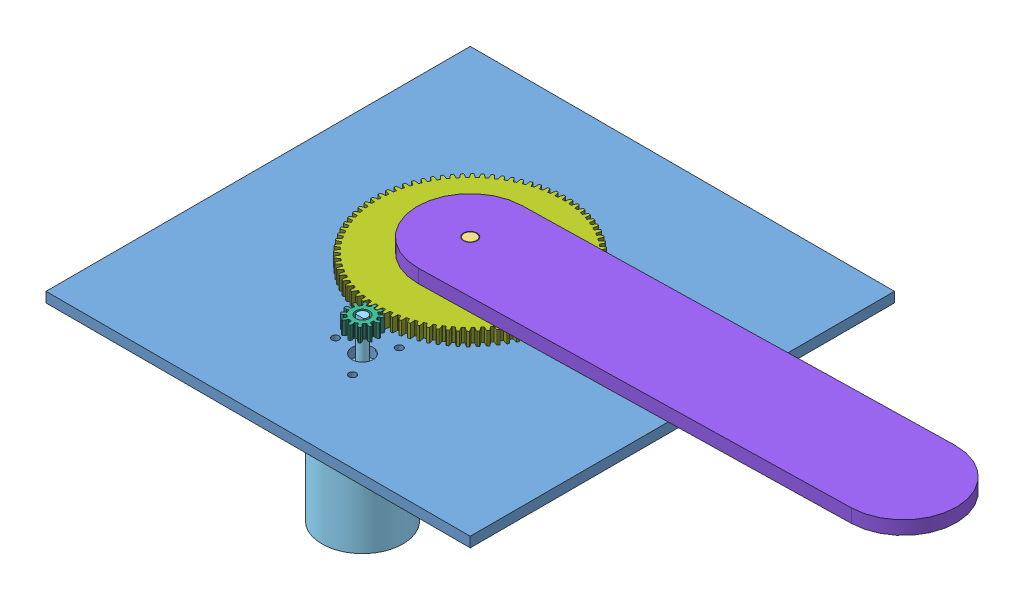
SolidWorks assembly turntable, configuration Default. Lengths in mm.
Overall size (325.48 90.47 200).
14 component instances, 11 part files, 24 mates.
Components (placement in the parent):
- base plate-1: base plate [Default] at (2.5629 -8.9842 3.1335) size (200 4.76 200)
- generic_flanged_ball_bearing-1: generic_flanged_ball_bearing [0.250 x 0.625] at (2.5629 -8.1333 3.1335) x (0 1 0) z (-0.546944 0 0.837169) size (4.98 17.53 17.53)
- generic_dowel_pin-1: generic_dowel_pin [0.25 x 2] at (2.5629 -7.4094 3.1335) x (0 1 0) z (-0.184773 0 -0.982781) size (50.8 6.35 6.35)
- generic_shaft_clamp-1: generic_shaft_clamp [0.25] at (2.5629 1.3219 3.1335) x (0.929398 0 -0.36908) z (0 -1 0) size (17.46 17.45 7.94)
- generic_small_motor-1: generic_small_motor [Default] at (2.5629 -8.9842 53.9335) x (-1 0 0) z (0 1 0) size (38.1 38.1 88.9)
- spur_gear_12_tooth_24_pitch-1: spur_gear_12_tooth_24_pitch [Default] at (2.5629 5.2906 53.9335) x (-0.128453 0 -0.991716) z (0.991716 0 -0.128453) size (14.82 6.35 14.82)
- spur_gear_84_tooth_24_pitch-1: spur_gear_84_tooth_24_pitch [Default] at (2.5629 5.2906 3.1335) x (0.999778 0 -0.021061) z (0.021061 0 0.999778) size (91.02 6.35 91.02)
- rotor-1: rotor [Default] at (2.5629 11.6406 3.1335) x (0.999778 0 -0.021061) z (0.021061 0 0.999778) size (250 6.35 50)
- lower bearing plate-1: lower bearing plate [Default] at (2.5629 -34.3842 3.1335) size (50 6.35 50)
- generic ball bearing-2: generic ball bearing [0.250 x 0.75] at (2.5629 -27.2404 3.1335) x (0 -1 0) z (-0.049783 0 0.99876) size (7.14 19.05 19.05)
- round_threaded_spacer-1: round_threaded_spacer [4-40 x 0.750] at (-18.4371 -8.9842 -17.8665) x (0.531357 0 0.847148) z (0 1 0) size (6.35 6.35 19.05)
- round_threaded_spacer-2: round_threaded_spacer [4-40 x 0.750] at (-18.4371 -8.9842 24.1335) x (0.531357 0 0.847148) z (0 1 0) size (6.35 6.35 19.05)
- round_threaded_spacer-3: round_threaded_spacer [4-40 x 0.750] at (23.5629 -8.9842 -17.8665) x (0.531357 0 0.847148) z (0 1 0) size (6.35 6.35 19.05)
- round_threaded_spacer-4: round_threaded_spacer [4-40 x 0.750] at (23.5629 -8.9842 24.1335) x (0.531357 0 0.847148) z (0 1 0) size (6.35 6.35 19.05)
Mates (geometry in assembly coordinates):
- Concentric1: concentric aligned: cylinder of base plate-1 through (2.5629 -4.2217 3.1335) axis (0 -1 0) radius 7.9375; cylinder of generic_flanged_ball_bearing-1 through (2.5629 -12.9653 3.1335) axis (0 -1 0) radius 7.9375
- Concentric2: concentric aligned: cylinder of generic_flanged_ball_bearing-1 through (2.5629 -12.9653 3.1335) axis (0 -1 0) radius 3.175; cylinder of generic_dowel_pin-1 through (2.5629 17.9906 3.1335) axis (0 -1 0) radius 3.175
- Concentric3: concentric anti-aligned: cylinder of generic_dowel_pin-1 through (2.5629 17.9906 3.1335) axis (0 -1 0) radius 3.175; cylinder of generic_shaft_clamp-1 through (2.5629 -2.6469 3.1335) axis (0 1 0) radius 3.175
- Coincident2: coincident anti-aligned: plane of base plate-1 through (2.5629 -8.9842 3.1335) normal (0 -1 0); plane of generic_small_motor-1 through (2.5629 -8.9842 53.9335) normal (0 1 0)
- Concentric4: concentric aligned: cylinder of generic_dowel_pin-1 through (2.5629 17.9906 3.1335) axis (0 -1 0) radius 3.175; cylinder of spur_gear_84_tooth_24_pitch-1 through (2.5629 11.6406 3.1335) axis (0 -1 0) radius 3.175
- Coincident3: coincident anti-aligned: plane of generic_shaft_clamp-1 through (2.5629 5.2906 3.1335) normal (0 1 0); plane of spur_gear_84_tooth_24_pitch-1 through (2.5629 5.2906 3.1335) normal (0 -1 0)
- Concentric5: concentric aligned: cylinder of generic_small_motor-1 through (2.5629 16.4158 53.9335) axis (0 -1 0) radius 2.3813; cylinder of spur_gear_12_tooth_24_pitch-1 through (2.5629 11.6406 53.9335) axis (0 -1 0) radius 3.175
- Coincident4: coincident aligned: plane of spur_gear_12_tooth_24_pitch-1 through (2.5629 11.6406 53.9335) normal (0 1 0); plane of spur_gear_84_tooth_24_pitch-1 through (2.5629 11.6406 3.1335) normal (0 1 0)
- Distance1: distance = 50.8 mm: axis of generic_dowel_pin-1 through (2.5629 17.7366 3.1335) axis (0 -1 0); axis of generic_small_motor-1 through (2.5629 -72.4842 53.9335) axis (0 1 0)
- Concentric7: concentric anti-aligned: cylinder of generic_dowel_pin-1 through (2.5629 17.9906 3.1335) axis (0 -1 0) radius 3.175; cylinder of rotor-1 through (2.5629 11.6406 3.1335) axis (0 1 0) radius 3.175
- Coincident10: coincident anti-aligned: plane of spur_gear_84_tooth_24_pitch-1 through (2.5629 11.6406 3.1335) normal (0 1 0); plane of rotor-1 through (2.5629 11.6406 3.1335) normal (0 -1 0)
- Coincident6: coincident aligned: plane of generic_dowel_pin-1 through (2.5629 17.9906 3.1335) normal (0 1 0); plane of rotor-1 through (2.5629 17.9906 3.1335) normal (0 1 0)
- Concentric8: concentric aligned: cylinder of generic_dowel_pin-1 through (2.5629 17.9906 3.1335) axis (0 -1 0) radius 3.175; cylinder of lower bearing plate-1 through (2.5629 -28.0342 3.1335) axis (0 -1 0) radius 9.525
- Concentric9: concentric anti-aligned: cylinder of lower bearing plate-1 through (2.5629 -28.0342 3.1335) axis (0 -1 0) radius 9.525; cylinder of generic ball bearing-2 through (2.5629 -22.4084 3.1335) axis (0 1 0) radius 9.525
- Coincident9: coincident aligned: plane of lower bearing plate-1 through (2.5629 -34.3842 3.1335) normal (0 -1 0); plane of generic ball bearing-2 through (10.8077 -34.3842 3.5445) normal (0 -1 0)
- Coincident11: coincident anti-aligned: plane of base plate-1 through (2.5629 -8.9842 3.1335) normal (0 -1 0); plane of round_threaded_spacer-1 through (-18.4371 -8.9842 -17.8665) normal (0 1 0)
- Concentric10: concentric aligned: cylinder of lower bearing plate-1 through (-18.4371 -28.0342 -17.8665) axis (0 1 0) radius 1.632; cylinder of round_threaded_spacer-1 through (-18.4371 -28.0342 -17.8665) axis (0 1 0) radius 1.1303
- Coincident12: coincident anti-aligned: plane of lower bearing plate-1 through (2.5629 -28.0342 3.1335) normal (0 1 0); plane of round_threaded_spacer-1 through (-18.4371 -28.0342 -17.8665) normal (0 -1 0)
- Parallel1: parallel aligned: plane of base plate-1 through (-97.4371 -4.2217 -96.8665) normal (-1 0 0); plane of lower bearing plate-1 through (-22.4371 -28.0342 -21.8665) normal (-1 0 0)
- Coincident14: coincident anti-aligned: plane of base plate-1 through (2.5629 -4.2217 3.1335) normal (0 1 0); plane of generic_flanged_ball_bearing-1 through (-4.7732 -4.2217 -1.6594) normal (0 -1 0)
- Distance6: distance = 0.508 mm anti-aligned: plane of generic_shaft_clamp-1 through (2.5629 -2.6469 3.1335) normal (0 -1 0); plane of generic_flanged_ball_bearing-1 through (-0.0951 -3.1549 1.397) normal (0 1 0)
- Parallel2: parallel aligned: plane of spur_gear_84_tooth_24_pitch-1 through (2.5629 5.2906 3.1335) normal (0.021061 0 0.999778); plane of rotor-1 through (3.0894 17.9906 28.128) normal (0.021061 0 0.999778)
- GearMate1: gear = 12 : 84 mm: axis of spur_gear_84_tooth_24_pitch-1 through (2.5629 11.6406 3.1335) axis (0 -1 0); axis of spur_gear_12_tooth_24_pitch-1 through (2.5629 11.6406 53.9335) axis (0 -1 0)
- Coincident21: coincident anti-aligned: plane of base plate-1 through (2.5629 -8.9842 3.1335) normal (1 0 0); plane of generic_small_motor-1
